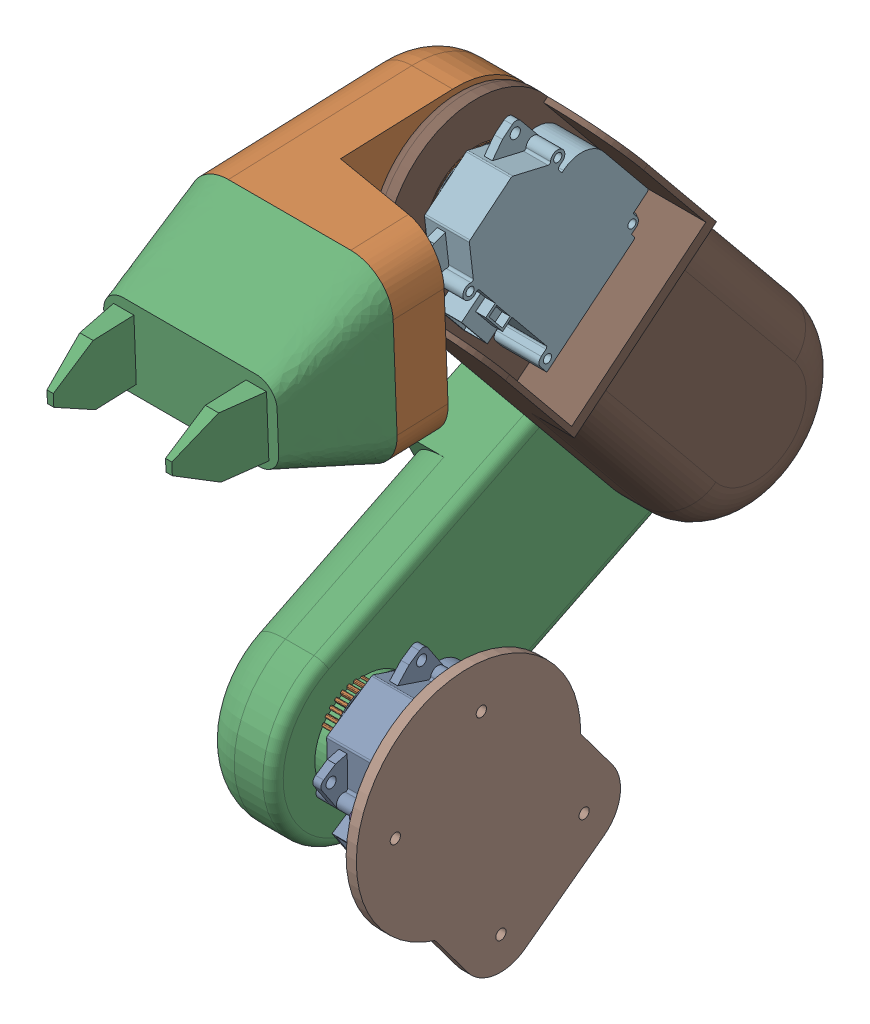
SolidWorks assembly Assem1, configuration Default. Lengths in mm.
Overall size (100.08 342.11 352.55).
12 component instances, 7 part files, 24 mates.
Components (placement in the parent):
- ARM1-1: ARM1 [Default] at (-8.5697 -32.6451 15.5777) (suppressed, hidden)
- Actuator Motor-1: Actuator Motor [Default] at (2.4303 74.4697 41.3524) x (0 -0.831409 -0.555661) z (0 -0.555661 0.831409) size (94.34 34.5 77)
- Gear1-1: Gear1 [Default] at (-8.5697 92.3762 59.4914) x (0 -1 0) z (0 0 1) size (36 10 35.98)
- Part4-2: Part4 [Default] at (-8.5697 86.0744 54.5898) x (0 0.442758 -0.896641) z (1 0 0) size (260 90 50)
- Part5-1: Part5 [Default] at (41.3423 29.3687 21.9791) x (0 -0.949357 0.3142) z (-1 0 0) size (129.02 137.22 20) (hidden)
- Actuator Motor-2: Actuator Motor [Default] at (-19.5697 154.0645 -72.9803) x (0 -0.442758 0.896641) z (0 -0.896641 -0.442758) size (94.34 34.5 77)
- Gear1-2: Gear1 [Default] at (-18.5697 160.5334 -97.4588) x (0 -0.938523 -0.345217) z (0 -0.345217 0.938523) size (36 10 35.98)
- Part4-3: Part4 [Default] at (-8.5697 161.4665 -97.2702) x (0 0.77403 0.633149) z (-1 0 0) size (260 90 50)
- Actuator Motor-3: Actuator Motor [Default] at (2.4303 276.1408 -9.2557) x (0 -0.77403 -0.633149) z (0 -0.633149 0.77403) size (94.34 34.5 77)
- Gear1-3: Gear1 [Default] at (1.4303 292.2659 10.6047) x (0 -0.381849 0.924225) z (0 -0.924225 -0.381849) size (36 10 35.98)
- Part6-1: Part6 [Default] at (-8.5697 292.7494 10.5013) x (0 -0.038306 0.999266) z (1 0 0) size (135 90 100)
- graber-1: graber [Default] at (1.4303 289.316 100.0636) x (1 0 0) z (0 -0.999266 -0.038306) size (100.08 90.07 90.08)
Mates (geometry in assembly coordinates):
- Coincident1: coincident anti-aligned: plane of ARM1-1 through (1.4303 82.9806 53.9865) normal (1 0 0); plane of Actuator Motor-1 through (1.4303 92.8822 59.0467) normal (-1 0 0)
- Concentric1: concentric anti-aligned: cylinder of Actuator Motor-1 through (-10.0697 92.9563 59.1204) axis (1 0 0) radius 4.5; cylinder of Gear1-1 through (1.4303 92.9563 59.1204) axis (-1 0 0) radius 5
- Coincident2: coincident anti-aligned: plane of Actuator Motor-1 through (1.4303 92.8822 59.0467) normal (-1 0 0); plane of Gear1-1 through (1.4303 92.9563 59.1204) normal (1 0 0)
- Concentric3: concentric anti-aligned: cylinder of ARM1-1 through (-114.4047 85.9097 54.9233) axis (1 0 0) radius 25; cylinder of Part4-2 through (1.4303 85.9097 54.9233) axis (-1 0 0) radius 24.5
- Tangent1: tangent: curve of ARM1-1; circle of Part5-1
- Parallel1: parallel anti-aligned: plane of ARM1-1 through (1.4303 82.9806 53.9865) normal (1 0 0); plane of Part5-1 through (36.3423 82.9806 53.9865) normal (-1 0 0)
- Concentric5: concentric anti-aligned: cylinder of ARM1-1 through (-114.4047 85.9097 54.9233) axis (1 0 0) radius 25; cylinder of Part4-2 through (1.4303 85.9097 54.9233) axis (-1 0 0) radius 24.5
- Coincident9: coincident anti-aligned: plane of Part4-2 through (-18.5697 86.0744 54.5898) normal (-1 0 0); plane of Actuator Motor-2 through (-18.5697 161.1785 -97.5057) normal (1 0 0)
- Parallel3: parallel anti-aligned: plane of Part4-2 through (-18.5697 199.2858 -78.6885) normal (0 -0.896641 -0.442758); plane of Actuator Motor-2 through (-41.5697 185.4648 -57.4749) normal (0 0.896641 0.442758)
- Concentric6: concentric anti-aligned: cylinder of Part4-2 through (1.4303 161.1785 -97.5057) axis (-1 0 0) radius 25; circle of Actuator Motor-2
- Coincident15: coincident anti-aligned: plane of ARM1-1 through (-8.5697 83.6039 54.5802) normal (-1 0 0); plane of Part4-2 through (-8.5697 85.9097 54.9233) normal (1 0 0)
- Concentric8: concentric aligned: cylinder of Actuator Motor-2 through (-7.0697 161.2059 -97.6067) axis (-1 0 0) radius 4.5; cylinder of Gear1-2 through (-8.5697 161.2059 -97.6067) axis (-1 0 0) radius 5
- Coincident16: coincident anti-aligned: plane of Actuator Motor-2 through (-18.5697 161.1785 -97.5057) normal (1 0 0); plane of Gear1-2 through (-18.5697 161.2059 -97.6067) normal (-1 0 0)
- Concentric9: concentric anti-aligned: cylinder of Part4-2 through (1.4303 161.1785 -97.5057) axis (-1 0 0) radius 25; cylinder of Part4-3 through (-18.5697 161.1785 -97.5057) axis (1 0 0) radius 24.5
- Coincident18: coincident anti-aligned: plane of Part4-3 through (1.4303 161.4665 -97.2702) normal (1 0 0); plane of Actuator Motor-3 through (1.4303 292.7636 10.1296) normal (-1 0 0)
- Concentric18: concentric anti-aligned: cylinder of Part4-3 through (-18.5697 292.7636 10.1296) axis (1 0 0) radius 25; circle of Actuator Motor-3
- Parallel5: parallel anti-aligned: plane of Part4-3 through (1.4303 259.1505 -72.273) normal (0 0.77403 0.633149); plane of Actuator Motor-3 through (24.4303 250.8303 -29.9594) normal (0 -0.77403 -0.633149)
- Coincident21: coincident anti-aligned: plane of Actuator Motor-3 through (1.4303 292.7636 10.1296) normal (-1 0 0); plane of Gear1-3 through (1.4303 292.8303 10.2102) normal (1 0 0)
- Concentric19: concentric aligned: cylinder of Actuator Motor-3 through (-10.0697 292.8303 10.2102) axis (1 0 0) radius 4.5; cylinder of Gear1-3 through (-8.5697 292.8303 10.2102) axis (1 0 0) radius 5
- Coincident22: coincident anti-aligned: plane of Part4-2 through (-8.5697 85.9097 54.9233) normal (1 0 0); plane of Part4-3 through (-8.5697 161.1785 -97.5057) normal (-1 0 0)
- Concentric20: concentric anti-aligned: cylinder of Part4-3 through (-18.5697 292.7636 10.1296) axis (1 0 0) radius 25; cylinder of Part6-1 through (1.4303 292.7636 10.1296) axis (-1 0 0) radius 24.5
- Coincident23: coincident anti-aligned: plane of Part4-3 through (-8.5697 161.1785 -97.5057) normal (-1 0 0); plane of Part6-1 through (-8.5697 292.7636 10.1296) normal (1 0 0)
- Coincident24: coincident anti-aligned: line of Part6-1 through (-28.5697 334.283 101.7874) axis (1 0 0); line of graber-1 through (31.4303 334.283 101.7874) axis (-1 0 0)
- Coincident25: coincident anti-aligned: line of Part6-1 through (51.4303 314.2977 101.0212) axis (0 -0.999266 -0.038306); line of graber-1 through (51.4303 264.3344 99.1059) axis (0 0.999266 0.038306)
